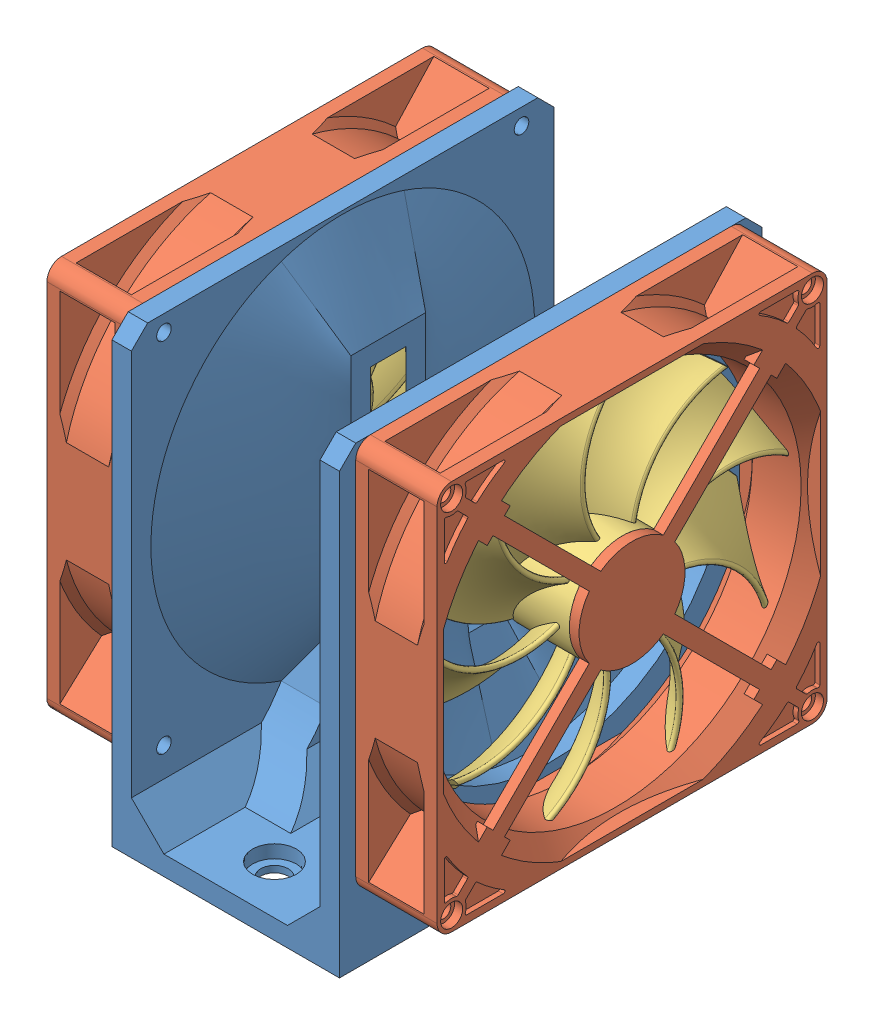
SolidWorks assembly Cooling_station, configuration Default. Lengths in mm.
Overall size (128.39 183.8 184.17).
7 component instances, 3 part files, 4 mates.
Components (placement in the parent):
- Fan mount-1: Fan mount [Default] at (-1.1456 -39.3695 -38.3244) size (70 141.99 130)
- PC FAN-1: PC FAN [Default] at (46.3544 -29.3695 26.6756) x (0 0 1) z (-1 0 0) size (183.81 183.8 33.39)
  - CPU Fan with no fan-1: CPU Fan with no fan [Default] at origin size (120 120 33.39)
  - Part3^PC FAN-1: Part3^PC FAN [Default] at (0 0 -9.5) x (-0.828072 -0.560621 0) z (0 0 1) size (132.38 132.34 22) (virtual)
- PC FAN-2: PC FAN [Default] at (-48.6456 -29.3695 26.6756) x (0 0 -1) z (1 0 0) size (183.81 183.8 33.39)
  - CPU Fan with no fan-1: CPU Fan with no fan [Default] at origin size (120 120 33.39)
  - Part3^PC FAN-1: Part3^PC FAN [Default] at (0 0 -9.5) x (-0.828072 -0.560621 0) z (0 0 1) size (132.38 132.34 22) (virtual)
Mates (geometry in assembly coordinates):
- Concentric1: concentric anti-aligned: cylinder of Fan mount-1 through (-96.1456 -29.3695 26.6756) axis (1 0 0) radius 55; cylinder of PC FAN-2/Part3^PC FAN-1 through (-36.1456 -29.3695 26.6756) axis (-1 0 0) radius 16.3
- Coincident1: coincident anti-aligned: plane of Fan mount-1 through (-36.1456 -109.3695 91.6756) normal (-1 0 0); plane of PC FAN-2/CPU Fan with no fan-1 through (-36.1456 -84.8695 82.1756) normal (1 0 0)
- Concentric2: concentric aligned: cylinder of Fan mount-1 through (-96.1456 -29.3695 26.6756) axis (1 0 0) radius 55; cylinder of PC FAN-1/Part3^PC FAN-1 through (33.8544 -29.3695 26.6756) axis (1 0 0) radius 16.3
- Coincident3: coincident anti-aligned: plane of Fan mount-1 through (33.8544 -109.3695 91.6756) normal (1 0 0); plane of PC FAN-1/CPU Fan with no fan-1 through (33.8544 -84.8695 -28.8244) normal (-1 0 0)
